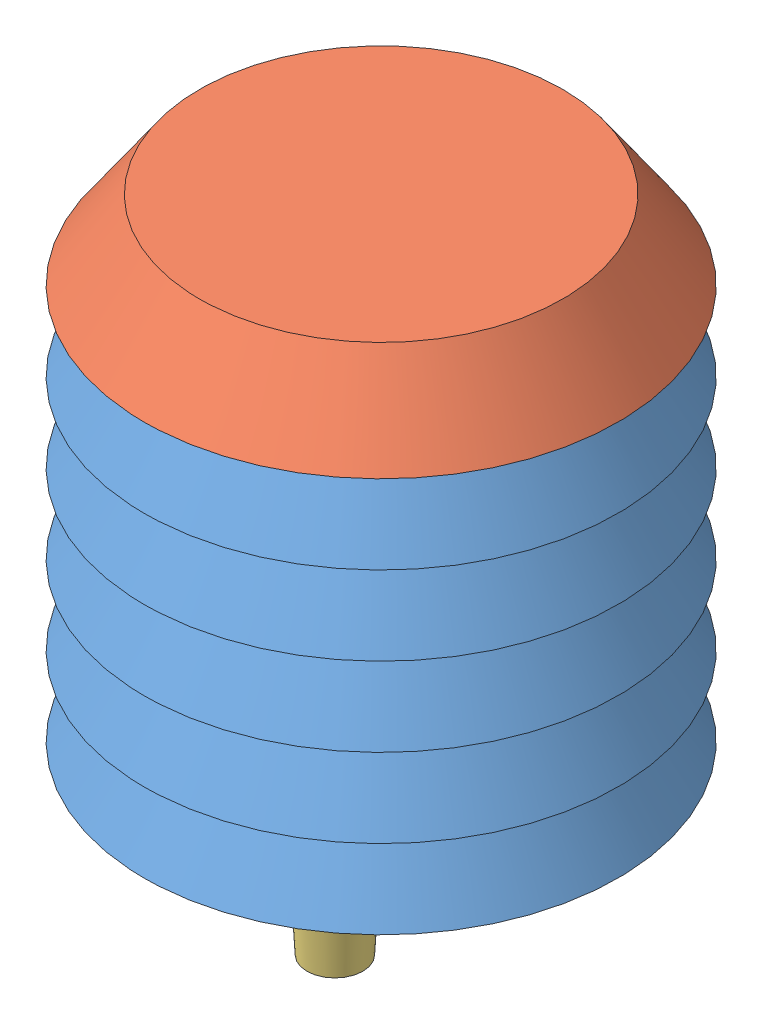
SolidWorks assembly radiation shield, configuration Défaut. Lengths in mm.
Overall size (61.47 72.5 61.47).
9 component instances, 4 part files, 19 mates.
Components (placement in the parent):
- element-1: element [Défaut] at (1.2109 -9.1474 0) size (60 10 60)
- element-2: element [Défaut] at (1.2109 0.8526 0) size (60 10 60)
- element-3: element [Défaut] at (1.2109 10.8526 0) size (60 10 60)
- element-4: element [Défaut] at (1.2109 30.8526 0) size (60 10 60)
- element-5: element [Défaut] at (1.2109 20.8526 0) size (60 10 60)
- socle-1: socle [Défaut] at (1.2109 -9.1474 0) x (-0.5 0 0.866025) z (0.866025 0 0.5) size (45 20.5 45) (hidden)
- chapeau-1: chapeau [Défaut] at (1.2109 40.8526 0) size (60 10 60)
- socle-2: socle [Défaut] at (1.2109 -9.1474 0) x (-0.5 0 -0.866025) z (-0.866025 0 0.5) size (45 20.5 45)
- support-1: support [Défaut] at (1.2109 -8.8974 0) x (0.27717 0 -0.960821) z (0.960821 0 0.27717) size (22 61.5 16.5)
Mates (geometry in assembly coordinates):
- Coïncidente1: coincident anti-aligned: plane of element-1 through (1.2109 0.8526 0) normal (0 1 0); plane of element-2 through (1.2109 0.8526 0) normal (0 -1 0)
- Coaxiale1: concentric aligned: cylinder of element-1 through (1.2109 7.8526 0) axis (0 -1 0) radius 8.5; cylinder of element-2 through (1.2109 17.8526 0) axis (0 -1 0) radius 8.5
- Coïncidente2: coincident anti-aligned: plane of element-2 through (1.2109 10.8526 0) normal (0 1 0); plane of element-3 through (1.2109 10.8526 0) normal (0 -1 0)
- Coaxiale2: concentric aligned: cylinder of element-2 through (1.2109 17.8526 0) axis (0 -1 0) radius 8.5; cylinder of element-3 through (1.2109 27.8526 0) axis (0 -1 0) radius 8.5
- Coïncidente4: coincident anti-aligned: plane of element-3 through (1.2109 20.8526 0) normal (0 1 0); plane of element-5 through (1.2109 20.8526 0) normal (0 -1 0)
- Coaxiale3: concentric aligned: cylinder of element-3 through (1.2109 27.8526 0) axis (0 -1 0) radius 8.5; cylinder of element-5 through (1.2109 37.8526 0) axis (0 -1 0) radius 8.5
- Coïncidente5: coincident anti-aligned: plane of element-4 through (1.2109 30.8526 0) normal (0 -1 0); plane of element-5 through (1.2109 30.8526 0) normal (0 1 0)
- Coaxiale4: concentric aligned: cylinder of element-4 through (1.2109 47.8526 0) axis (0 -1 0) radius 8.5; cylinder of element-5 through (1.2109 37.8526 0) axis (0 -1 0) radius 8.5
- Coaxiale6: concentric aligned: circle of socle-1; circle of element-1
- Coïncidente8: coincident anti-aligned: plane of element-1 through (1.2109 -9.1474 0) normal (0 -1 0); plane of socle-1 through (1.2109 -9.1474 0) normal (0 1 0)
- Coaxiale7: concentric aligned: circle of element-1; circle of socle-1
- Coïncidente10: coincident anti-aligned: plane of element-4 through (1.2109 40.8526 0) normal (0 1 0); plane of chapeau-1 through (1.2109 40.8526 0) normal (0 -1 0)
- Coaxiale8: concentric aligned: circle of element-4; circle of chapeau-1
- Coïncidente12: coincident anti-aligned: plane of element-1 through (1.2109 -9.1474 0) normal (0 -1 0); plane of socle-2 through (1.2109 -9.1474 0) normal (0 1 0)
- Coaxiale9: concentric aligned: cylinder of element-1 through (1.2109 7.8526 0) axis (0 -1 0) radius 8.5; cylinder of socle-2 through (1.2109 -9.1464 0) axis (0 -1 0) radius 8.5
- Coaxiale10: concentric aligned: cone of element-1 through (-14.7891 -9.1474 0) axis (0 -1 0); circle of socle-2
- Coaxiale11: concentric: cylinder of socle-2 through (1.2109 -9.1464 0) axis (0 -1 0) radius 8.5; cylinder of support-1 through (1.2109 -4.6474 0) axis (0 -1 0) radius 8.25
- Coïncidente15: coincident: plane of socle-2 through (1.2109 -13.1474 0) normal (0 -1 0); plane of support-1 through (1.2109 -13.1474 0) normal (0 -1 0)
- Parallèle2: parallel anti-aligned: plane of socle-2 through (-1.9904 -1.1474 11.0975) normal (-0.960821 0 -0.27717); plane of support-1 through (3.8532 -4.6474 0.7622) normal (0.960821 0 0.27717)
